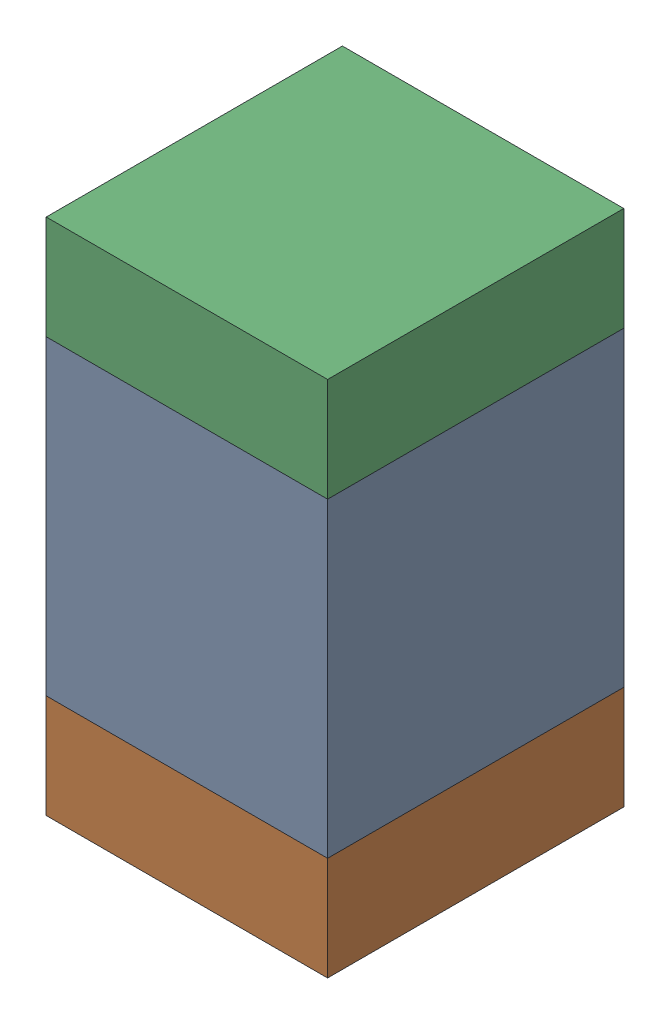
SolidWorks assembly C7-1, configuration Default. Lengths in mm.
Overall size (0.95 1.75 1).
6 component instances, 2 part files, 0 mates.
Components (placement in the parent):
- 959208528-1-1: 959208528-1 [Default] at (145.288 83.8282 0) size (0.95 1.05 1)
  - Extruded-46-1: Extruded-46 [Default] at origin size (0.95 1.05 1)
- 959208664-1-1: 959208664-1 [Default] at (145.288 83.1282 0) size (0.95 0.35 1)
  - Extruded-45-1: Extruded-45 [Default] at origin size (0.95 0.35 1)
- 959208664-1-2: 959208664-1 [Default] at (145.288 84.5282 0) size (0.95 0.35 1)
  - Extruded-45-1: Extruded-45 [Default] at origin size (0.95 0.35 1)
